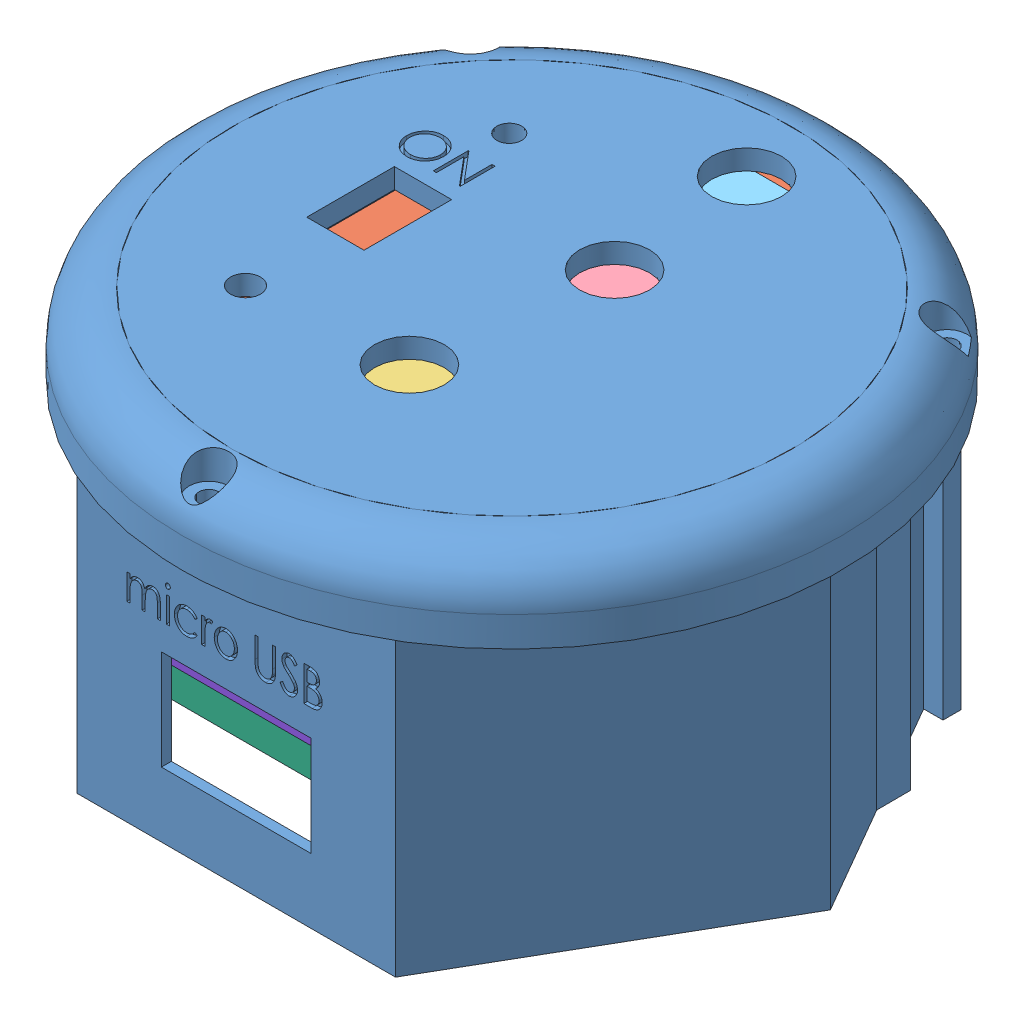
SolidWorks assembly PAYLOAD_ASSEMB, configuration Default. Lengths in mm.
Overall size (66 38.22 66).
12 component instances, 11 part files, 4 mates.
Components (placement in the parent):
- payload-1: payload [Default] at (22.1791 14.4009 49.2678) size (66 38.22 66)
- perf_payload-1: perf_payload [Default] at (122.376 44.4009 26.7635) size (47.68 22.8 56.41)
  - perfboard_pl-1: perfboard_pl [Default] at origin size (47.68 1.7 56.41)
  - CCS811-1: CCS811 [Default] at (-63.7913 1.6 50.697) size (21 2 18)
  - ISL29125-1: ISL29125 [Default] at (-81.9294 1.6 26.7737) size (18.5 2 18)
  - VEML6070-1: VEML6070 [Default] at (-58.9407 1.6 11.4703) size (13.5 2 13)
  - featherM0LORA-1: featherM0LORA [Default] at (-99.6799 -17.2 -2.9628) size (23 4 51)
  - SMD Switch-1: SMD Switch [Default] at (-114.5109 -3.1 22.6076) x (0 0 -1) z (1 0 0) size (8.7 9.4 3.86)
  - perfboard_pl_2-1: perfboard_pl_2 [Default] at (0 -15.2 0) size (33.78 1.6 56.41)
  - perfboard_pl_3-1: perfboard_pl_3 [Default] at (-14.0679 -9.6 -10.7999) size (8.64 1.6 33.02)
  - Micro SD-1: Micro SD [Default] at (-101.2748 -13.6 13.7688) x (0 0 1) z (0 1 0) size (31.75 25.4 3.4)
  - Lipo750A-1: Lipo750A [Default] at (-91.5331 -3.0405 -3.4133) x (0.999963 0 -0.008628) z (0.008628 0 0.999963) size (22 8 50)
Mates (geometry in assembly coordinates):
- Distance1: distance = 0 mm anti-aligned: plane of payload-1 through (22.1791 46.0009 49.2678) normal (0 -1 0); plane of perf_payload-1/perfboard_pl-1 through (22.1791 46.0009 49.2678) normal (0 1 0)
- Coincident1: coincident anti-aligned: plane of perf_payload-1/perfboard_pl-1 through (22.1791 40.8009 49.2678) normal (0 -1 0); plane of ? through (10.9944 40.8009 74.3041) normal (0 1 0)
- Distance2: distance = 0.05 mm anti-aligned: plane of perf_payload-1/perfboard_pl-1 through (6.8431 46.0009 75.8306) normal (0 0 1); plane of payload-1 through (37.544 44.4009 75.8806) normal (0 0 -1)
- Distance3: distance = 0.05 mm anti-aligned: plane of perf_payload-1/perfboard_pl-1 through (-1.5007 46.0009 37.1569) normal (-1 0 0); plane of payload-1 through (-1.5507 46.0009 61.3922) normal (1 0 0)
